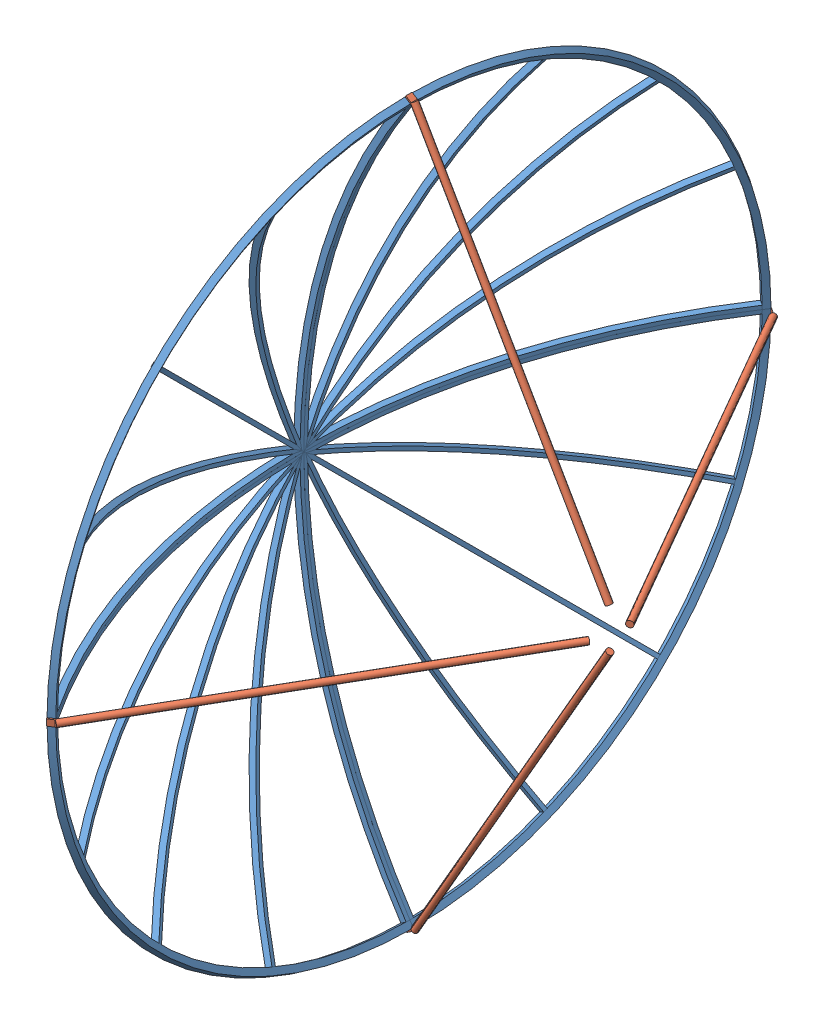
SolidWorks assembly DishAssembly, configuration Default. Lengths in mm.
Overall size (999.14 2301.7 2301.7).
8 component instances, 2 part files, 23 mates.
Components (placement in the parent):
- DishQuarter-1: DishQuarter [Default] at (-269.9978 97.1957 586.6141) size (367.72 1146.68 1146.68)
- DishQuarter-2: DishQuarter [Default] at (-269.9978 97.1957 586.6141) x (1 0 0) z (0 0 -1) size (367.72 1146.68 1146.68)
- DishQuarter-3: DishQuarter [Default] at (-269.9978 97.1957 586.6141) x (1 0 0) z (0 -1 0) size (367.72 1146.68 1146.68)
- DishQuarter-4: DishQuarter [Default] at (-269.9978 97.1957 586.6141) x (1 0 0) z (0 1 0) size (367.72 1146.68 1146.68)
- DishStrut-1: DishStrut [Default] at (100.4769 1237.0074 576.6141) x (1 -0.000899 0) z (0 0 1) size (648.1 1089.89 20)
- DishStrut-2: DishStrut [Default] at (100.4769 105.1957 1726.4258) x (1 0 -0.000899) z (0 -1 0) size (648.1 1089.89 20)
- DishStrut-4: DishStrut [Default] at (100.4769 65.1957 -553.1976) x (1 0 0.000899) z (0 1 0) size (648.1 1089.89 20)
- DishStrut-5: DishStrut [Default] at (100.4769 -1042.616 594.6141) x (1 0.000899 0) z (0 0 -1) size (648.1 1089.89 20)
Mates (geometry in assembly coordinates):
- Coincident1: coincident: plane of DishQuarter-1 through (1777.7922 97.1957 586.6141) normal (0 0 -1); plane of DishQuarter-4 through (-269.9978 109.1957 586.6141) normal (0 0 1)
- Concentric1: concentric: cylinder of DishQuarter-1 through (1777.7922 97.1957 598.6141) axis (0 0 -1) radius 2027.79; cylinder of DishQuarter-4 through (1777.7922 97.1957 586.6141) axis (0 0 -1) radius 2027.79
- Coincident2: coincident: cone of DishQuarter-1 through (81.0385 97.1957 586.6141) axis (1 0 0); cone of DishQuarter-4 through (81.0385 97.1957 586.6141) axis (1 0 0)
- Coincident3: coincident: plane of DishQuarter-3 through (1777.7922 97.1957 586.6141) normal (0 1 0); plane of DishQuarter-4 through (1777.7922 97.1957 586.6141) normal (0 -1 0)
- Coincident4: coincident: cone of DishQuarter-1 through (81.0385 97.1957 586.6141) axis (1 0 0); cone of DishQuarter-3 through (81.0385 97.1957 586.6141) axis (1 0 0)
- Concentric2: concentric: cylinder of DishQuarter-1 through (1777.7922 97.1957 586.6141) axis (0 1 0) radius 2027.79; cylinder of DishQuarter-3 through (1777.7922 85.1957 586.6141) axis (0 1 0) radius 2027.79
- Coincident5: coincident: plane of DishQuarter-2 through (-269.9978 97.1957 574.6141) normal (0 1 0); plane of DishQuarter-4 through (1777.7922 97.1957 586.6141) normal (0 -1 0)
- Coincident6: coincident: plane of DishQuarter-2 through (1777.7922 97.1957 586.6141) normal (0 0 1); plane of DishQuarter-3 through (-269.9978 85.1957 586.6141) normal (0 0 -1)
- Concentric3: concentric: cylinder of DishQuarter-2 through (1777.7922 97.1957 586.6141) axis (0 -1 0) radius 2027.79; cylinder of DishQuarter-4 through (1777.7922 109.1957 586.6141) axis (0 -1 0) radius 2027.79
- Tangent1: tangent: cone of DishQuarter-4 through (81.0385 97.1957 586.6141) axis (1 0 0); plane of DishStrut-1 through (89.3782 1238.3557 596.6141) normal (-0.551814 -0.833967 0)
- Tangent2: tangent: cone of DishQuarter-4 through (70.0022 97.1957 586.6141) axis (-1 0 0); plane of DishStrut-1 through (83.7976 1248.0437 596.6141) normal (-0.833967 0.551814 0)
- Distance1: distance = 2 mm: plane of DishQuarter-1 through (1777.7922 97.1957 598.6141) normal (0 0 1); plane of DishStrut-1 through (100.4769 1237.0074 596.6141) normal (0 0 1)
- Tangent3: tangent: cone of DishQuarter-1 through (81.0385 97.1957 586.6141) axis (1 0 0); plane of DishStrut-4 through (89.3782 85.1957 -554.5459) normal (-0.551814 0 0.833967)
- Tangent4: tangent: cone of DishQuarter-1 through (70.0022 97.1957 586.6141) axis (-1 0 0); plane of DishStrut-4 through (83.7976 85.1957 -564.2338) normal (-0.833967 0 -0.551814)
- Coincident8: coincident: plane of DishQuarter-3 through (1777.7922 85.1957 586.6141) normal (0 -1 0); plane of DishStrut-4 through (100.4769 85.1957 -553.1976) normal (0 1 0)
- Tangent5: tangent: cone of DishQuarter-1 through (81.0385 97.1957 586.6141) axis (1 0 0); plane of DishStrut-2 through (89.3782 85.1957 1727.7741) normal (-0.551814 0 -0.833967)
- Coincident9: coincident: plane of DishQuarter-3 through (1777.7922 85.1957 586.6141) normal (0 -1 0); plane of DishStrut-2 through (100.4769 85.1957 1726.4258) normal (0 -1 0)
- Tangent6: tangent: cone of DishQuarter-3 through (70.0022 97.1957 586.6141) axis (-1 0 0); plane of DishStrut-2 through (83.7976 85.1957 1737.462) normal (-0.833967 0 0.551814)
- Coincident10: coincident: plane of DishQuarter-2 through (1777.7922 97.1957 574.6141) normal (0 0 -1); plane of ? through (1125.8973 558.5143 574.6141) normal (0 0 -1)
- Tangent7: tangent: cone of DishQuarter-3 through (81.0385 97.1957 586.6141) axis (1 0 0); plane of ? through (1131.4779 548.8263 574.6141) normal (-0.551814 -0.833967 0)
- Tangent10: tangent: cone of DishQuarter-2 through (81.0385 97.1957 586.6141) axis (1 0 0); plane of DishStrut-5 through (89.3782 -1043.9643 574.6141) normal (-0.551814 0.833967 0)
- Tangent11: tangent: cone of DishQuarter-4 through (70.0022 97.1957 586.6141) axis (-1 0 0); plane of DishStrut-5 through (83.7976 -1053.6522 574.6141) normal (-0.833967 -0.551814 0)
- Coincident11: coincident: plane of DishQuarter-2 through (1777.7922 97.1957 574.6141) normal (0 0 -1); plane of DishStrut-5 through (100.4769 -1042.616 574.6141) normal (0 0 -1)
